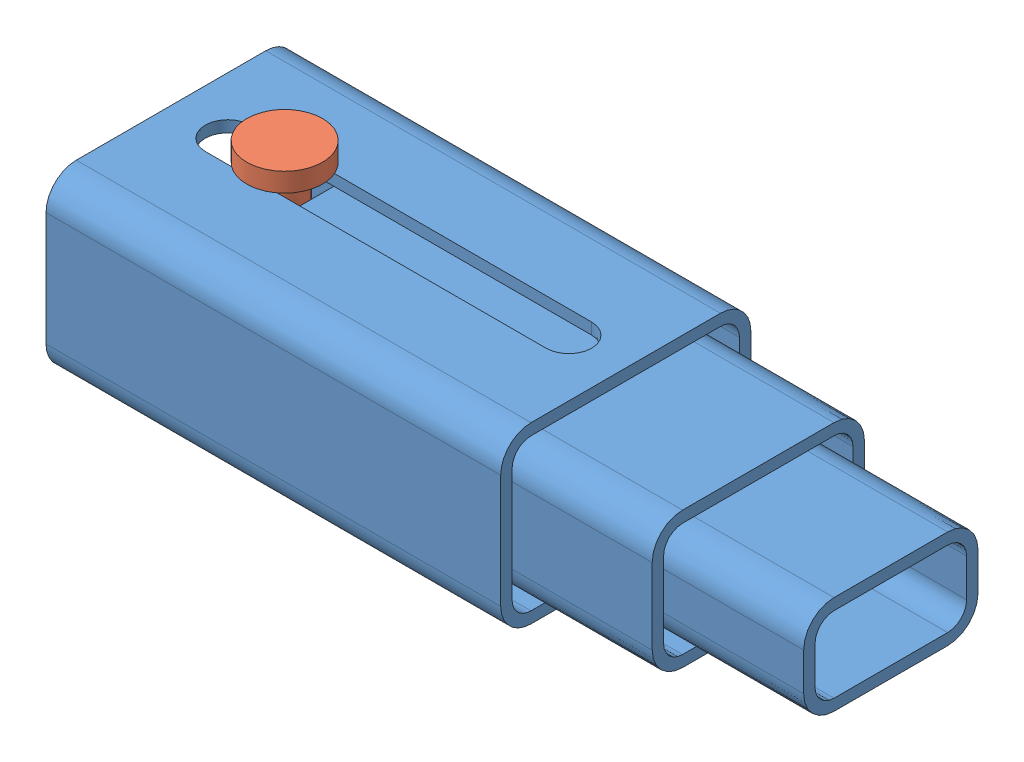
SolidWorks assembly Assem advanced and mechanical mates, configuration Default. Lengths in mm.
Overall size (189.95 60 66).
4 component instances, 2 part files, 9 mates.
Components (placement in the parent):
- Advanced and Mechanical Mates-1: Advanced and Mechanical Mates [Large] at (44.469 74.4118 84.2717) size (120 46 66)
- Advanced and Mechanical Mates-2: Advanced and Mechanical Mates [Medium] at (79.4459 74.4118 84.2717) size (120 36 56)
- Advanced and Mechanical Mates-3: Advanced and Mechanical Mates [Small] at (114.4227 74.4118 84.2717) size (120 26 46)
- Pin-1: Pin [Default] at (14.4459 74.4118 84.2717) x (-0.578948 0 0.815365) z (-0.815365 0 -0.578948) size (20 60 20)
Mates (geometry in assembly coordinates):
- Width1: width anti-aligned: plane of Advanced and Mechanical Mates-1 through (104.469 54.4118 109.2717) normal (0 1 0); plane of Advanced and Mechanical Mates-2 through (104.469 94.4118 109.2717) normal (0 -1 0); plane of Advanced and Mechanical Mates-1 through (139.4459 56.4118 104.2717) normal (0 -1 0); plane of Advanced and Mechanical Mates-2 through (139.4459 92.4118 104.2717) normal (0 1 0)
- Width2: width aligned: plane of Advanced and Mechanical Mates-1 through (104.469 89.4118 114.2717) normal (0 0 -1); plane of Advanced and Mechanical Mates-2 through (104.469 89.4118 54.2717) normal (0 0 1); plane of Advanced and Mechanical Mates-1 through (139.4459 84.4118 56.2717) normal (0 0 -1); plane of Advanced and Mechanical Mates-2 through (139.4459 84.4118 112.2717) normal (0 0 1)
- Width3: width anti-aligned: plane of Advanced and Mechanical Mates-2 through (139.4459 59.4118 104.2717) normal (0 1 0); plane of Advanced and Mechanical Mates-3 through (139.4459 89.4118 104.2717) normal (0 -1 0); plane of Advanced and Mechanical Mates-2 through (174.4227 61.4118 99.2717) normal (0 -1 0); plane of Advanced and Mechanical Mates-3 through (174.4227 87.4118 99.2717) normal (0 1 0)
- Width4: width anti-aligned: plane of Advanced and Mechanical Mates-2 through (139.4459 84.4118 59.2717) normal (0 0 1); plane of Advanced and Mechanical Mates-3 through (139.4459 84.4118 109.2717) normal (0 0 -1); plane of Advanced and Mechanical Mates-2 through (174.4227 79.4118 61.2717) normal (0 0 -1); plane of Advanced and Mechanical Mates-3 through (174.4227 79.4118 107.2717) normal (0 0 1)
- Coincident1: coincident aligned: plane of Advanced and Mechanical Mates-3 through (104.469 69.4118 99.2717) normal (1 0 0); plane of Advanced and Mechanical Mates-2 through (104.469 64.4118 104.2717) normal (1 0 0)
- Linear/Linear Coupler1: linear coupler = 1 : 2 mm: plane of Advanced and Mechanical Mates-2 through (139.4459 64.4118 104.2717) normal (1 0 0); plane of Advanced and Mechanical Mates-3 through (174.4227 69.4118 99.2717) normal (1 0 0)
- Slot1: slot anti-aligned: cylinder of Pin-1 through (14.4459 99.4118 84.2717) axis (0 -1 0) radius 5; cylinder of Advanced and Mechanical Mates-1 through (-0.531 51.4118 84.2717) axis (0 1 0) radius 6; cylinder of Advanced and Mechanical Mates-1 through (89.469 51.4118 84.2717) axis (0 1 0) radius 6
- Width5: width aligned: plane of Pin-1 through (14.4459 49.4118 84.2717) normal (0 1 0); plane of Advanced and Mechanical Mates-1 through (14.4459 99.4118 84.2717) normal (0 -1 0); plane of Pin-1 through (104.469 97.4118 109.2717) normal (0 1 0); plane of Advanced and Mechanical Mates-1 through (104.469 51.4118 109.2717) normal (0 -1 0)
- Tangent2: tangent anti-aligned: plane of Advanced and Mechanical Mates-2 through (19.4459 64.4118 104.2717) normal (-1 0 0); cylinder of Pin-1 through (14.4459 99.4118 84.2717) axis (0 -1 0) radius 5
